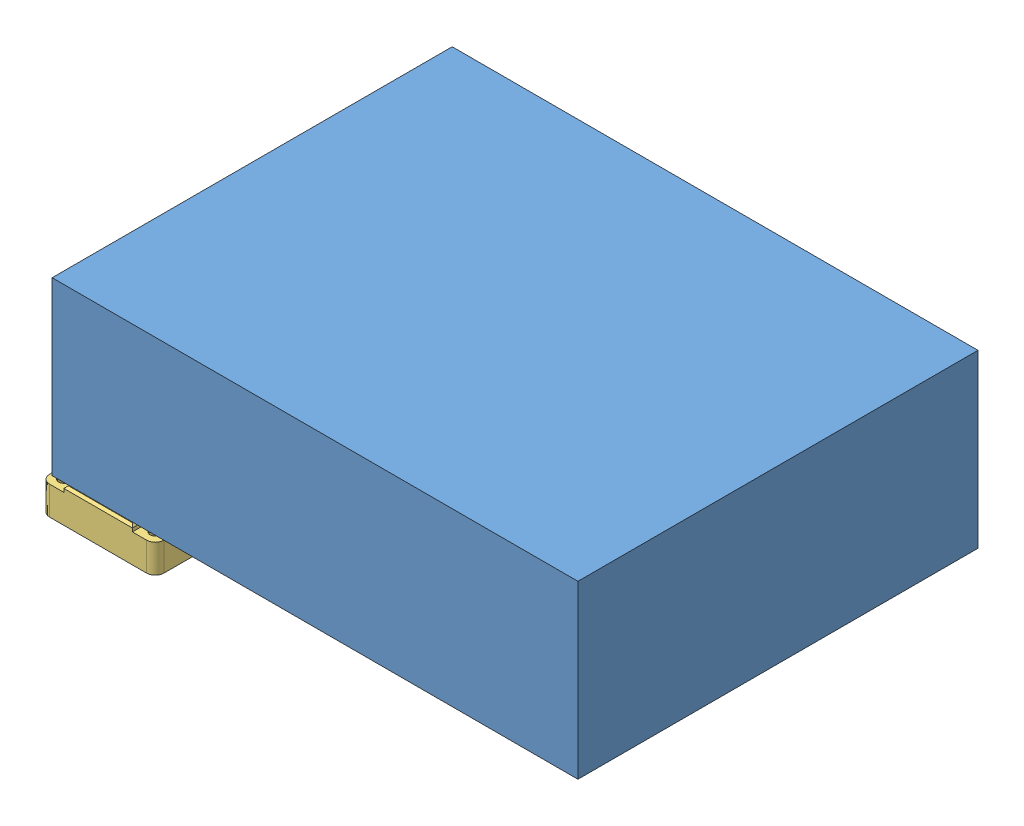
SolidWorks assembly charger-box-mount, configuration Default. Lengths in mm.
Overall size (187.9 73 140).
3 component instances, 3 part files, 6 mates.
Components (placement in the parent):
- charger^charger-box-mount-1: charger^charger-box-mount [Default] at origin size (184 60 140) (virtual)
- foot-1: foot [Default] at (-75.9 0 50) x (-1 0 0) z (0 0 1) size (24 12 124)
- latch^charger-box-mount-1: latch^charger-box-mount [Default] at origin size (40 12 125) (virtual)
Mates (geometry in assembly coordinates):
- Coincident1: coordinate: point of charger^charger-box-mount-1
- Coincident2: coincident anti-aligned: plane of charger^charger-box-mount-1 through (0 0 0) normal (0 -1 0); plane of foot-1 through (-75.9 0 41) normal (0 1 0)
- Concentric1: concentric aligned: cylinder of charger^charger-box-mount-1 through (-75.9 3 50) axis (0 -1 0) radius 1.5; cylinder of foot-1 through (-75.9 -55 50) axis (0 -1 0) radius 1.5
- Parallel1: parallel anti-aligned: plane of foot-1 through (-75.9 0 50) normal (-1 0 0)
- Coincident5: coordinate: unknown of latch^charger-box-mount-1
- Coincident6: coordinate: unknown of latch^charger-box-mount-1
